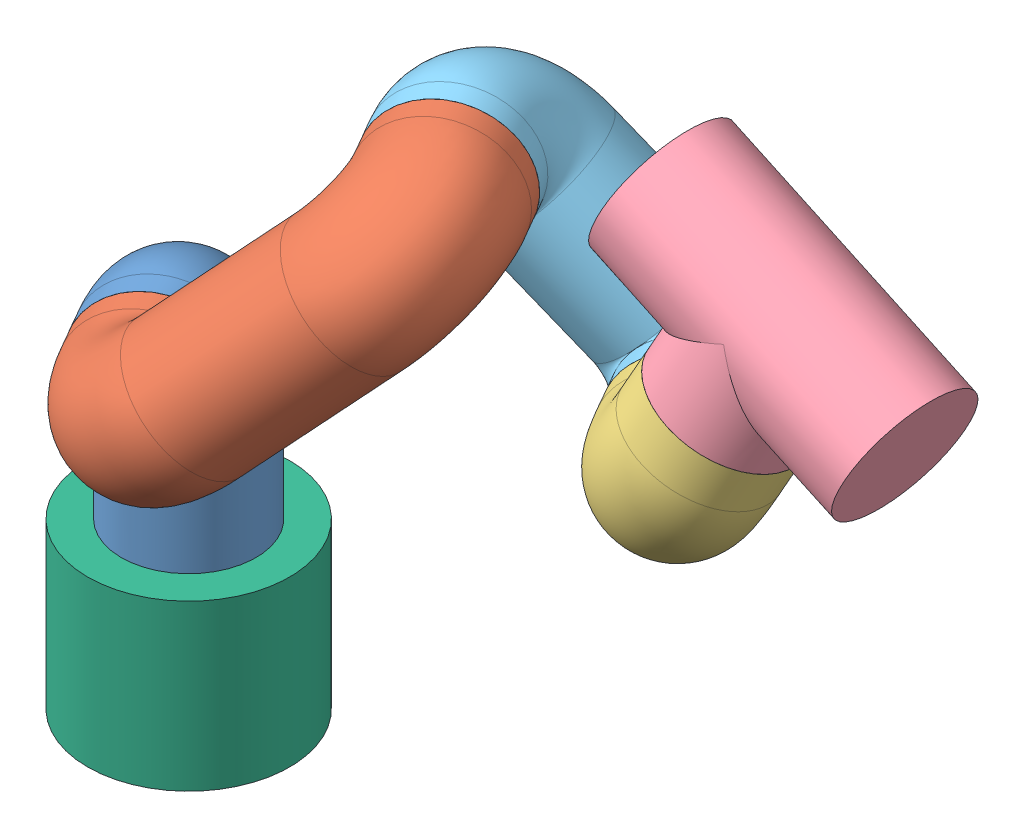
SolidWorks assembly myCobotMK1, configuration Default. Lengths in mm.
Overall size (284.24 251.71 208.78).
6 component instances, 6 part files, 10 mates.
Components (placement in the parent):
- baseArm-1: baseArm [Default] at (6.8769 25.6643 104.8034) x (0.49795 0 0.867206) z (-0.867206 0 0.49795) size (58.2 95.42 50)
- lowerArm-1: lowerArm [Default] at (23.4089 96.0843 133.5947) x (0.49795 0 0.867206) z (-0.601663 0.720173 0.345475) size (58.2 160.4 50)
- pitchArm-1: pitchArm [Default] at (149.9031 103.3054 60.9616) x (0.49795 0 0.867206) z (-0.768639 0.463036 0.441353) size (58.2 65 50)
- rollArm-1: rollArm [Default] at (150.2414 188.7187 72.416) x (0.91174 -0.410666 0.009182) z (0.086548 0.213906 0.973013) size (100 58.2 50)
- upperArm-1: upperArm [Default] at (92.3579 172.6792 94.0041) x (-0.49795 0 -0.867206) z (-0.626681 -0.69122 0.359841) size (58.2 146 50)
- basePlate-1: basePlate [Default] at (6.8769 -35.4857 104.8034) size (75 61.15 75)
Mates (geometry in assembly coordinates):
- Coincident1: coincident anti-aligned: plane of baseArm-1 through (23.4089 96.0843 133.5947) normal (0.49795 0 0.867206); plane of lowerArm-1 through (23.4089 96.0843 133.5947) normal (-0.49795 0 -0.867206)
- Coincident2: coincident: circle of baseArm-1; circle of lowerArm-1
- Coincident3: coincident anti-aligned: plane of lowerArm-1 through (92.3579 172.6792 94.0041) normal (-0.49795 0 -0.867206); plane of upperArm-1 through (92.3579 172.6792 94.0041) normal (0.49795 0 0.867206)
- Coincident4: coincident aligned: circle of lowerArm-1; circle of upperArm-1
- Coincident5: coincident anti-aligned: plane of pitchArm-1 through (149.9031 103.3054 60.9616) normal (-0.49795 0 -0.867206); plane of upperArm-1 through (149.9031 103.3054 60.9616) normal (0.49795 0 0.867206)
- Coincident6: coincident aligned: circle of pitchArm-1; circle of upperArm-1
- Coincident7: coincident anti-aligned: plane of pitchArm-1 through (182.497 138.759 80.53) normal (0.401547 0.886339 -0.230569); plane of rollArm-1 through (182.497 138.759 80.53) normal (-0.401547 -0.886339 0.230569)
- Coincident8: coincident aligned: circle of pitchArm-1; circle of rollArm-1
- Coincident11: coincident anti-aligned: plane of baseArm-1 through (6.8769 25.6643 104.8034) normal (0 -1 0); plane of basePlate-1 through (6.8769 25.6643 104.8034) normal (0 1 0)
- Concentric1: concentric aligned: circle of baseArm-1; circle of basePlate-1
